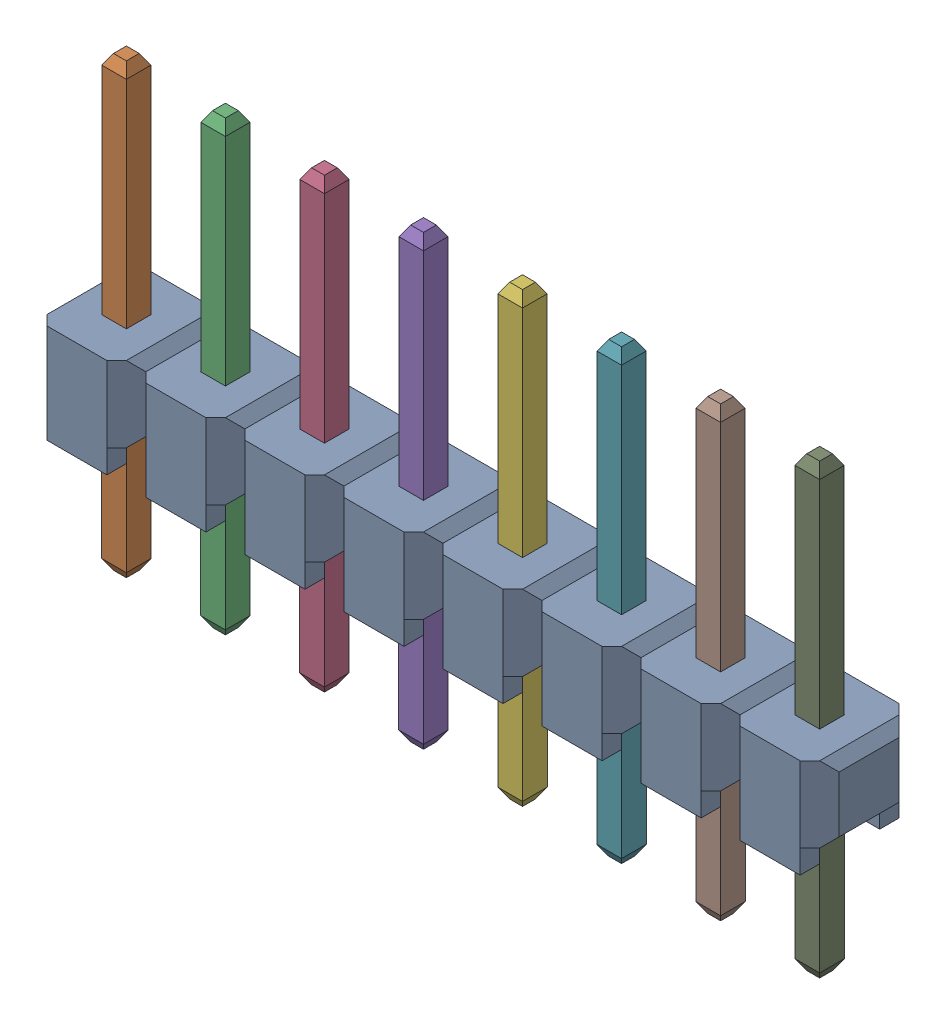
SolidWorks assembly m20-9770842_asm.stp.1, configuration Default. Lengths in mm.
Overall size (20.32 11.48 2.54).
10 component instances, 2 part files, 0 mates.
Components (placement in the parent):
- M20-977_ASM-1: M20-977_ASM [Default] at origin size (20.32 11.48 2.54)
  - M20-977-MOULD_2-1: M20-977-MOULD_2 [Default] at origin size (20.32 2.54 2.54)
  - M20-977-PIN.7-1: M20-977-PIN.7 [Default] at (2.54 -5.68 0) x (1 0 0) z (0 0 -1) size (0.64 11.48 0.64)
  - M20-977-PIN.7-2: M20-977-PIN.7 [Default] at (5.08 -5.68 0) x (1 0 0) z (0 0 -1) size (0.64 11.48 0.64)
  - M20-977-PIN.7-3: M20-977-PIN.7 [Default] at (7.62 -5.68 0) x (1 0 0) z (0 0 -1) size (0.64 11.48 0.64)
  - M20-977-PIN.7-4: M20-977-PIN.7 [Default] at (10.16 -5.68 0) x (1 0 0) z (0 0 -1) size (0.64 11.48 0.64)
  - M20-977-PIN.7-5: M20-977-PIN.7 [Default] at (12.7 -5.68 0) x (1 0 0) z (0 0 -1) size (0.64 11.48 0.64)
  - M20-977-PIN.7-6: M20-977-PIN.7 [Default] at (15.24 -5.68 0) x (1 0 0) z (0 0 -1) size (0.64 11.48 0.64)
  - M20-977-PIN.7-7: M20-977-PIN.7 [Default] at (17.78 -5.68 0) x (1 0 0) z (0 0 -1) size (0.64 11.48 0.64)
  - M20-977-PIN.7-8: M20-977-PIN.7 [Default] at (20.32 -5.68 0) x (1 0 0) z (0 0 -1) size (0.64 11.48 0.64)
